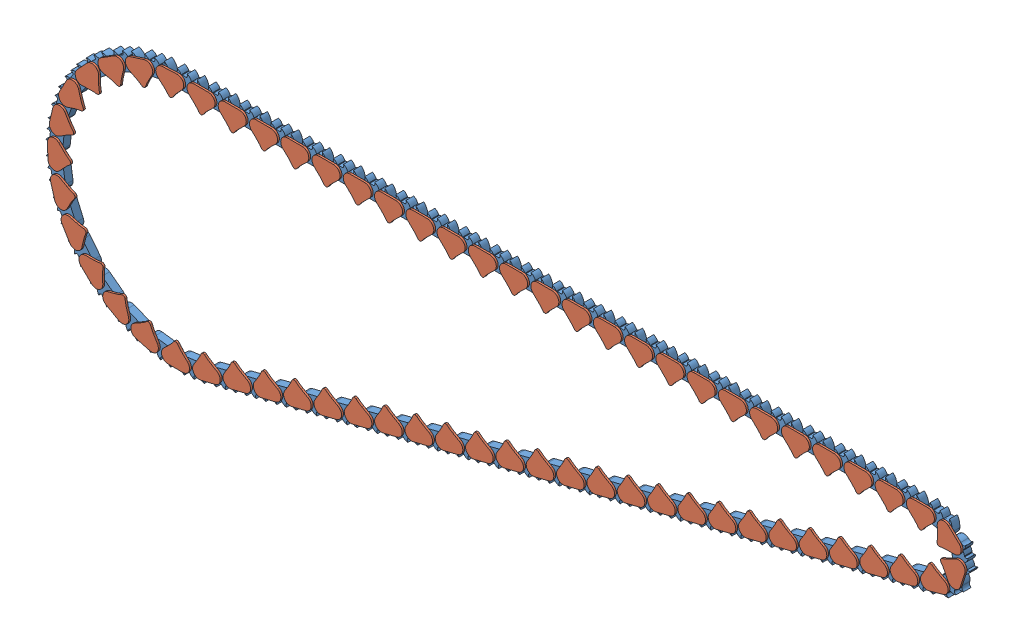
SolidWorks assembly Assem4, configuration Default. Lengths in mm.
Overall size (244.29 69.63 2.5).
128 component instances, 2 part files, 8 mates.
Components (placement in the parent):
- Teeth-4: Teeth [Default] at (43.2265 54.6348 715.1655) size (7.83 4.36 2)
- Inner Part-397: Inner Part [Default] at (44.3464 54.6348 717.6655) x (-1 0 0) z (0 0 -1) size (7.41 6.1 2.5)
- Inner Part-461: Inner Part [Default] at (52.5919 54.6348 717.6655) x (-1 0 0) z (0 0 -1) size (7.41 6.1 2.5)
- Inner Part-462: Inner Part [Default] at (60.8374 54.6348 717.6655) x (-1 0 0) z (0 0 -1) size (7.41 6.1 2.5)
- Inner Part-463: Inner Part [Default] at (69.0829 54.6348 717.6655) x (-1 0 0) z (0 0 -1) size (7.41 6.1 2.5)
- Inner Part-464: Inner Part [Default] at (77.3284 54.6348 717.6655) x (-1 0 0) z (0 0 -1) size (7.41 6.1 2.5)
- Inner Part-465: Inner Part [Default] at (84.7657 51.9541 717.6655) x (-0.719072 0.694936 0) z (0 0 -1) size (7.41 6.1 2.5)
- Inner Part-466: Inner Part [Default] at (86.0507 44.3857 717.6655) x (0.306758 0.951787 0) z (0 0 -1) size (7.41 6.1 2.5)
- Inner Part-467: Inner Part [Default] at (79.8862 39.5908 717.6655) x (0.9638 0.266626 0) z (0 0 -1) size (7.41 6.1 2.5)
- Inner Part-468: Inner Part [Default] at (71.8952 37.5594 717.6655) x (0.97022 0.242226 0) z (0 0 -1) size (7.41 6.1 2.5)
- Inner Part-469: Inner Part [Default] at (63.8952 35.5621 717.6655) x (0.97022 0.242226 0) z (0 0 -1) size (7.41 6.1 2.5)
- Inner Part-470: Inner Part [Default] at (55.8953 33.5649 717.6655) x (0.97022 0.242226 0) z (0 0 -1) size (7.41 6.1 2.5)
- Inner Part-471: Inner Part [Default] at (47.8954 31.5676 717.6655) x (0.97022 0.242226 0) z (0 0 -1) size (7.41 6.1 2.5)
- Inner Part-472: Inner Part [Default] at (39.8954 29.5703 717.6655) x (0.97022 0.242226 0) z (0 0 -1) size (7.41 6.1 2.5)
- Inner Part-473: Inner Part [Default] at (31.8955 27.573 717.6655) x (0.97022 0.242226 0) z (0 0 -1) size (7.41 6.1 2.5)
- Inner Part-474: Inner Part [Default] at (23.8955 25.5758 717.6655) x (0.97022 0.242226 0) z (0 0 -1) size (7.41 6.1 2.5)
- Inner Part-475: Inner Part [Default] at (15.8956 23.5785 717.6655) x (0.97022 0.242226 0) z (0 0 -1) size (7.41 6.1 2.5)
- Inner Part-476: Inner Part [Default] at (7.8956 21.5812 717.6655) x (0.97022 0.242226 0) z (0 0 -1) size (7.41 6.1 2.5)
- Inner Part-477: Inner Part [Default] at (-0.1043 19.5839 717.6655) x (0.97022 0.242226 0) z (0 0 -1) size (7.41 6.1 2.5)
- Inner Part-478: Inner Part [Default] at (-8.1043 17.5867 717.6655) x (0.97022 0.242226 0) z (0 0 -1) size (7.41 6.1 2.5)
- Inner Part-479: Inner Part [Default] at (-16.1042 15.5894 717.6655) x (0.97022 0.242226 0) z (0 0 -1) size (7.41 6.1 2.5)
- Inner Part-480: Inner Part [Default] at (-24.1042 13.5921 717.6655) x (0.97022 0.242226 0) z (0 0 -1) size (7.41 6.1 2.5)
- Inner Part-481: Inner Part [Default] at (-32.1041 11.5948 717.6655) x (0.97022 0.242226 0) z (0 0 -1) size (7.41 6.1 2.5)
- Inner Part-482: Inner Part [Default] at (-40.1041 9.5976 717.6655) x (0.97022 0.242226 0) z (0 0 -1) size (7.41 6.1 2.5)
- Inner Part-483: Inner Part [Default] at (-48.104 7.6003 717.6655) x (0.97022 0.242226 0) z (0 0 -1) size (7.41 6.1 2.5)
- Inner Part-484: Inner Part [Default] at (-56.104 5.603 717.6655) x (0.97022 0.242226 0) z (0 0 -1) size (7.41 6.1 2.5)
- Inner Part-485: Inner Part [Default] at (-64.1039 3.6057 717.6655) x (0.97022 0.242226 0) z (0 0 -1) size (7.41 6.1 2.5)
- Inner Part-486: Inner Part [Default] at (-72.1039 1.6085 717.6655) x (0.97022 0.242226 0) z (0 0 -1) size (7.41 6.1 2.5)
- Inner Part-487: Inner Part [Default] at (-80.1038 -0.3888 717.6655) x (0.97022 0.242226 0) z (0 0 -1) size (7.41 6.1 2.5)
- Inner Part-488: Inner Part [Default] at (-88.1038 -2.3861 717.6655) x (0.97022 0.242226 0) z (0 0 -1) size (7.41 6.1 2.5)
- Inner Part-489: Inner Part [Default] at (-96.1037 -4.3834 717.6655) x (0.97022 0.242226 0) z (0 0 -1) size (7.41 6.1 2.5)
- Inner Part-490: Inner Part [Default] at (-104.1036 -6.3806 717.6655) x (0.97022 0.242226 0) z (0 0 -1) size (7.41 6.1 2.5)
- Inner Part-491: Inner Part [Default] at (-112.1091 -8.3556 717.6655) x (0.972392 0.233354 0) z (0 0 -1) size (7.41 6.1 2.5)
- Inner Part-492: Inner Part [Default] at (-120.2796 -9.2438 717.6655) x (1 0.000812 0) z (0 0 -1) size (7.41 6.1 2.5)
- Inner Part-493: Inner Part [Default] at (-128.4071 -8.0524 717.6655) x (0.967188 -0.254061 0) z (0 0 -1) size (7.41 6.1 2.5)
- Inner Part-494: Inner Part [Default] at (-135.9625 -4.829 717.6655) x (0.870489 -0.492187 0) z (0 0 -1) size (7.41 6.1 2.5)
- Inner Part-495: Inner Part [Default] at (-142.4466 0.2141 717.6655) x (0.716217 -0.697877 0) z (0 0 -1) size (7.41 6.1 2.5)
- Inner Part-496: Inner Part [Default] at (-147.4298 6.7441 717.6655) x (0.514468 -0.85751 0) z (0 0 -1) size (7.41 6.1 2.5)
- Inner Part-497: Inner Part [Default] at (-150.5815 14.3297 717.6655) x (0.278517 -0.960431 0) z (0 0 -1) size (7.41 6.1 2.5)
- Inner Part-498: Inner Part [Default] at (-151.6917 22.4685 717.6655) x (0.023989 -0.999712 0) z (0 0 -1) size (7.41 6.1 2.5)
- Inner Part-499: Inner Part [Default] at (-150.6861 30.6209 717.6655) x (-0.232183 -0.972672 0) z (0 0 -1) size (7.41 6.1 2.5)
- Inner Part-500: Inner Part [Default] at (-147.6315 38.246 717.6655) x (-0.472925 -0.881103 0) z (0 0 -1) size (7.41 6.1 2.5)
- Inner Part-501: Inner Part [Default] at (-142.7308 44.8382 717.6655) x (-0.682219 -0.731147 0) z (0 0 -1) size (7.41 6.1 2.5)
- Inner Part-502: Inner Part [Default] at (-136.3099 49.9612 717.6655) x (-0.846209 -0.532851 0) z (0 0 -1) size (7.41 6.1 2.5)
- Inner Part-503: Inner Part [Default] at (-128.7945 53.2767 717.6655) x (-0.954121 -0.299422 0) z (0 0 -1) size (7.41 6.1 2.5)
- Inner Part-504: Inner Part [Default] at (-120.6822 54.5689 717.6655) x (-0.998885 -0.047212 0) z (0 0 -1) size (7.41 6.1 2.5)
- Inner Part-505: Inner Part [Default] at (-112.4382 54.6348 717.6655) x (-1 0 0) z (0 0 -1) size (7.41 6.1 2.5)
- Inner Part-506: Inner Part [Default] at (-104.1927 54.6348 717.6655) x (-1 0 0) z (0 0 -1) size (7.41 6.1 2.5)
- Inner Part-507: Inner Part [Default] at (-95.9472 54.6348 717.6655) x (-1 0 0) z (0 0 -1) size (7.41 6.1 2.5)
- Inner Part-508: Inner Part [Default] at (-87.7017 54.6348 717.6655) x (-1 0 0) z (0 0 -1) size (7.41 6.1 2.5)
- Inner Part-509: Inner Part [Default] at (-79.4562 54.6348 717.6655) x (-1 0 0) z (0 0 -1) size (7.41 6.1 2.5)
- Inner Part-510: Inner Part [Default] at (-71.2107 54.6348 717.6655) x (-1 0 0) z (0 0 -1) size (7.41 6.1 2.5)
- Inner Part-511: Inner Part [Default] at (-62.9652 54.6348 717.6655) x (-1 0 0) z (0 0 -1) size (7.41 6.1 2.5)
- Inner Part-512: Inner Part [Default] at (-54.7197 54.6348 717.6655) x (-1 0 0) z (0 0 -1) size (7.41 6.1 2.5)
- Inner Part-513: Inner Part [Default] at (-46.4742 54.6348 717.6655) x (-1 0 0) z (0 0 -1) size (7.41 6.1 2.5)
- Inner Part-514: Inner Part [Default] at (-38.2287 54.6348 717.6655) x (-1 0 0) z (0 0 -1) size (7.41 6.1 2.5)
- Inner Part-515: Inner Part [Default] at (-29.9832 54.6348 717.6655) x (-1 0 0) z (0 0 -1) size (7.41 6.1 2.5)
- Inner Part-516: Inner Part [Default] at (-21.7377 54.6348 717.6655) x (-1 0 0) z (0 0 -1) size (7.41 6.1 2.5)
- Inner Part-517: Inner Part [Default] at (-13.4922 54.6348 717.6655) x (-1 0 0) z (0 0 -1) size (7.41 6.1 2.5)
- Inner Part-518: Inner Part [Default] at (-5.2467 54.6348 717.6655) x (-1 0 0) z (0 0 -1) size (7.41 6.1 2.5)
- Inner Part-519: Inner Part [Default] at (2.9988 54.6348 717.6655) x (-1 0 0) z (0 0 -1) size (7.41 6.1 2.5)
- Inner Part-520: Inner Part [Default] at (11.2443 54.6348 717.6655) x (-1 0 0) z (0 0 -1) size (7.41 6.1 2.5)
- Inner Part-521: Inner Part [Default] at (19.4898 54.6348 717.6655) x (-1 0 0) z (0 0 -1) size (7.41 6.1 2.5)
- Inner Part-522: Inner Part [Default] at (27.7353 54.6348 717.6655) x (-1 0 0) z (0 0 -1) size (7.41 6.1 2.5)
- Teeth-576: Teeth [Default] at (51.472 54.6348 715.1655) size (7.83 4.36 2)
- Teeth-577: Teeth [Default] at (59.7176 54.6348 715.1655) size (7.83 4.36 2)
- Teeth-578: Teeth [Default] at (67.9631 54.6348 715.1655) size (7.83 4.36 2)
- Teeth-579: Teeth [Default] at (76.2675 55.176 715.1655) x (0.976586 -0.215125 0) z (0 0 1) size (7.83 4.36 2)
- Teeth-580: Teeth [Default] at (85.1582 53.4245 715.1655) x (0.242969 -0.970034 0) z (0 0 1) size (7.83 4.36 2)
- Teeth-581: Teeth [Default] at (87.5449 44.6799 715.1655) x (-0.764135 -0.645057 0) z (0 0 1) size (7.83 4.36 2)
- Teeth-582: Teeth [Default] at (80.9817 39.828 715.1655) x (-0.97022 -0.242226 0) z (0 0 1) size (7.83 4.36 2)
- Teeth-583: Teeth [Default] at (72.9817 37.8307 715.1655) x (-0.97022 -0.242226 0) z (0 0 1) size (7.83 4.36 2)
- Teeth-584: Teeth [Default] at (64.9818 35.8334 715.1655) x (-0.97022 -0.242226 0) z (0 0 1) size (7.83 4.36 2)
- Teeth-585: Teeth [Default] at (56.9818 33.8361 715.1655) x (-0.97022 -0.242226 0) z (0 0 1) size (7.83 4.36 2)
- Teeth-586: Teeth [Default] at (48.9819 31.8389 715.1655) x (-0.97022 -0.242226 0) z (0 0 1) size (7.83 4.36 2)
- Teeth-587: Teeth [Default] at (40.9819 29.8416 715.1655) x (-0.97022 -0.242226 0) z (0 0 1) size (7.83 4.36 2)
- Teeth-588: Teeth [Default] at (32.982 27.8443 715.1655) x (-0.97022 -0.242226 0) z (0 0 1) size (7.83 4.36 2)
- Teeth-589: Teeth [Default] at (24.982 25.847 715.1655) x (-0.97022 -0.242226 0) z (0 0 1) size (7.83 4.36 2)
- Teeth-590: Teeth [Default] at (16.9821 23.8498 715.1655) x (-0.97022 -0.242226 0) z (0 0 1) size (7.83 4.36 2)
- Teeth-591: Teeth [Default] at (8.9821 21.8525 715.1655) x (-0.97022 -0.242226 0) z (0 0 1) size (7.83 4.36 2)
- Teeth-592: Teeth [Default] at (0.9822 19.8552 715.1655) x (-0.97022 -0.242226 0) z (0 0 1) size (7.83 4.36 2)
- Teeth-593: Teeth [Default] at (-7.0178 17.8579 715.1655) x (-0.97022 -0.242226 0) z (0 0 1) size (7.83 4.36 2)
- Teeth-594: Teeth [Default] at (-15.0177 15.8606 715.1655) x (-0.97022 -0.242226 0) z (0 0 1) size (7.83 4.36 2)
- Teeth-595: Teeth [Default] at (-23.0177 13.8634 715.1655) x (-0.97022 -0.242226 0) z (0 0 1) size (7.83 4.36 2)
- Teeth-596: Teeth [Default] at (-31.0176 11.8661 715.1655) x (-0.97022 -0.242226 0) z (0 0 1) size (7.83 4.36 2)
- Teeth-597: Teeth [Default] at (-39.0176 9.8688 715.1655) x (-0.97022 -0.242226 0) z (0 0 1) size (7.83 4.36 2)
- Teeth-598: Teeth [Default] at (-47.0175 7.8715 715.1655) x (-0.97022 -0.242226 0) z (0 0 1) size (7.83 4.36 2)
- Teeth-599: Teeth [Default] at (-55.0174 5.8743 715.1655) x (-0.97022 -0.242226 0) z (0 0 1) size (7.83 4.36 2)
- Teeth-600: Teeth [Default] at (-63.0174 3.877 715.1655) x (-0.97022 -0.242226 0) z (0 0 1) size (7.83 4.36 2)
- Teeth-601: Teeth [Default] at (-71.0173 1.8797 715.1655) x (-0.97022 -0.242226 0) z (0 0 1) size (7.83 4.36 2)
- Teeth-602: Teeth [Default] at (-79.0173 -0.1176 715.1655) x (-0.97022 -0.242226 0) z (0 0 1) size (7.83 4.36 2)
- Teeth-603: Teeth [Default] at (-87.0172 -2.1148 715.1655) x (-0.97022 -0.242226 0) z (0 0 1) size (7.83 4.36 2)
- Teeth-604: Teeth [Default] at (-95.0172 -4.1121 715.1655) x (-0.97022 -0.242226 0) z (0 0 1) size (7.83 4.36 2)
- Teeth-605: Teeth [Default] at (-103.0171 -6.1094 715.1655) x (-0.97022 -0.242226 0) z (0 0 1) size (7.83 4.36 2)
- Teeth-606: Teeth [Default] at (-110.9718 -8.356 715.1655) x (-0.991605 -0.129307 0) z (0 0 1) size (7.83 4.36 2)
- Teeth-607: Teeth [Default] at (-119.1803 -9.5661 715.1655) x (-0.991815 0.127684 0) z (0 0 1) size (7.83 4.36 2)
- Teeth-608: Teeth [Default] at (-127.4263 -8.6443 715.1655) x (-0.926524 0.376235 0) z (0 0 1) size (7.83 4.36 2)
- Teeth-609: Teeth [Default] at (-135.1651 -5.6514 715.1655) x (-0.800002 0.599998 0) z (0 0 1) size (7.83 4.36 2)
- Teeth-610: Teeth [Default] at (-141.8853 -0.7846 715.1655) x (-0.620513 0.784196 0) z (0 0 1) size (7.83 4.36 2)
- Teeth-611: Teeth [Default] at (-147.1421 5.6352 715.1655) x (-0.399834 0.916587 0) z (0 0 1) size (7.83 4.36 2)
- Teeth-612: Teeth [Default] at (-150.5865 13.184 715.1655) x (-0.152534 0.988298 0) z (0 0 1) size (7.83 4.36 2)
- Teeth-613: Teeth [Default] at (-151.9892 21.3621 715.1655) x (0.10497 0.994475 0) z (0 0 1) size (7.83 4.36 2)
- Teeth-614: Teeth [Default] at (-151.2564 29.6272 715.1655) x (0.355522 0.934668 0) z (0 0 1) size (7.83 4.36 2)
- Teeth-615: Teeth [Default] at (-148.4366 37.4309 715.1655) x (0.582432 0.81288 0) z (0 0 1) size (7.83 4.36 2)
- Teeth-616: Teeth [Default] at (-143.7173 44.2555 715.1655) x (0.770632 0.637281 0) z (0 0 1) size (7.83 4.36 2)
- Teeth-617: Teeth [Default] at (-137.4122 49.6494 715.1655) x (0.907708 0.419603 0) z (0 0 1) size (7.83 4.36 2)
- Teeth-618: Teeth [Default] at (-129.9399 53.2562 715.1655) x (0.984692 0.174303 0) z (0 0 1) size (7.83 4.36 2)
- Teeth-619: Teeth [Default] at (-121.8036 54.6348 715.1655) size (7.83 4.36 2)
- Teeth-620: Teeth [Default] at (-113.5581 54.6348 715.1655) size (7.83 4.36 2)
- Teeth-621: Teeth [Default] at (-105.3126 54.6348 715.1655) size (7.83 4.36 2)
- Teeth-622: Teeth [Default] at (-97.0671 54.6348 715.1655) size (7.83 4.36 2)
- Teeth-623: Teeth [Default] at (-88.8216 54.6348 715.1655) size (7.83 4.36 2)
- Teeth-624: Teeth [Default] at (-80.5761 54.6348 715.1655) size (7.83 4.36 2)
- Teeth-625: Teeth [Default] at (-72.3306 54.6348 715.1655) size (7.83 4.36 2)
- Teeth-626: Teeth [Default] at (-64.0851 54.6348 715.1655) size (7.83 4.36 2)
- Teeth-627: Teeth [Default] at (-55.8396 54.6348 715.1655) size (7.83 4.36 2)
- Teeth-628: Teeth [Default] at (-47.5941 54.6348 715.1655) size (7.83 4.36 2)
- Teeth-629: Teeth [Default] at (-39.3486 54.6348 715.1655) size (7.83 4.36 2)
- Teeth-630: Teeth [Default] at (-31.1031 54.6348 715.1655) size (7.83 4.36 2)
- Teeth-631: Teeth [Default] at (-22.8576 54.6348 715.1655) size (7.83 4.36 2)
- Teeth-632: Teeth [Default] at (-14.612 54.6348 715.1655) size (7.83 4.36 2)
- Teeth-633: Teeth [Default] at (-6.3665 54.6348 715.1655) size (7.83 4.36 2)
- Teeth-634: Teeth [Default] at (1.879 54.6348 715.1655) size (7.83 4.36 2)
- Teeth-635: Teeth [Default] at (10.1245 54.6348 715.1655) size (7.83 4.36 2)
- Teeth-636: Teeth [Default] at (18.37 54.6348 715.1655) size (7.83 4.36 2)
- Teeth-637: Teeth [Default] at (26.6155 54.6348 715.1655) size (7.83 4.36 2)
- Inner Part-524: Inner Part [Default] at (35.9808 54.6348 717.6655) x (-1 0 0) z (0 0 -1) size (7.41 6.1 2.5)
- Teeth-639: Teeth [Default] at (34.861 54.6348 715.1655) size (7.83 4.36 2)
Mates (geometry in assembly coordinates):
- Coincident1: coincident: point of Teeth-4; line of assembly
- Coincident2: coincident: point of Teeth-4; line of assembly
- Coincident4: coincident: point of Teeth-4; line of assembly
- Coincident5: coincident: point of Teeth-4; line of assembly
- Coincident6: coincident: point of Teeth-4; line of assembly
- Concentric3: concentric: circle of Teeth-4; cylinder of Inner Part-397 through (41.8306 54.6348 717.6655) axis (0 0 -1) radius 0.6
- Parallel6: parallel: plane of ? through (11.7863 54.6348 716.1655) normal (0 0 -1); plane of assembly through (0 0 0) normal (0 0 1)
- Parallel7: parallel: plane of ? through (-47.1695 54.6348 716.1655) normal (0 0 -1); plane of assembly through (0 0 0) normal (0 0 1)
